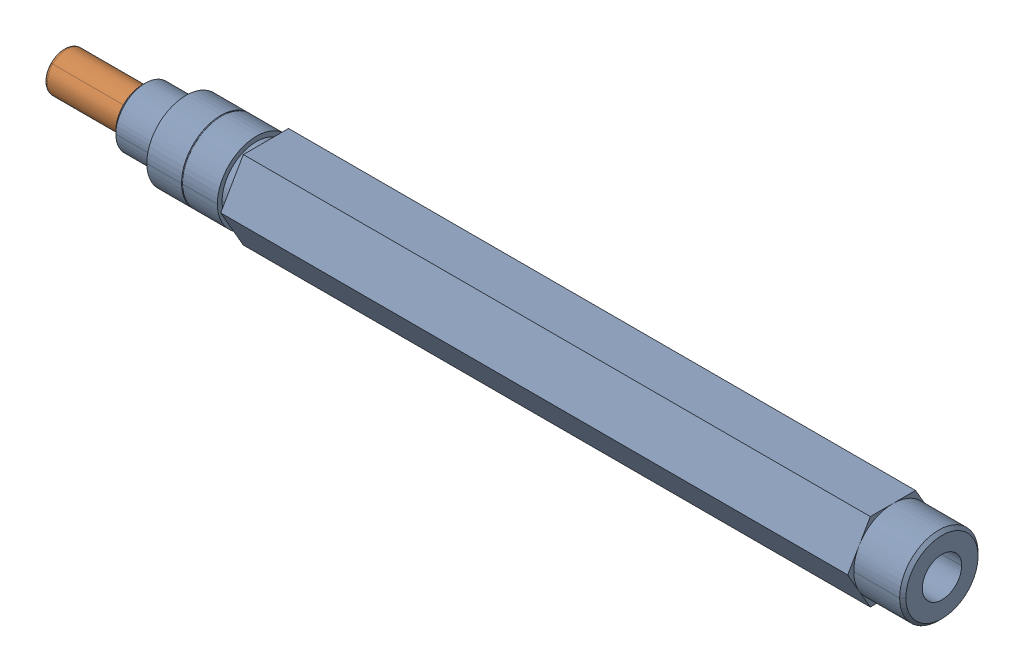
SolidWorks assembly am-4722 am-4722_pin am-4722_mag ToughBox S AM14U Length Hex Output Shaft_Inboard Pin, configuration Default. Lengths in mm.
Overall size (142.3 12.7 14.66).
2 component instances, 2 part files, 0 mates.
Components (placement in the parent):
- am-4722 ToughBox S AM14U Length Hex Output Shaft-1: am-4722 ToughBox S AM14U Length Hex Output Shaft [Default] at (-23.6192 60.5661 108.0804) size (129.6 12.7 14.66)
- 250x1000_dowel-1: 250x1000_dowel [Default] at (-36.3192 60.5661 108.0804) x (0 0.71632 -0.697772) z (0 -0.697772 -0.71632) size (6.35 25.4 6.35)
